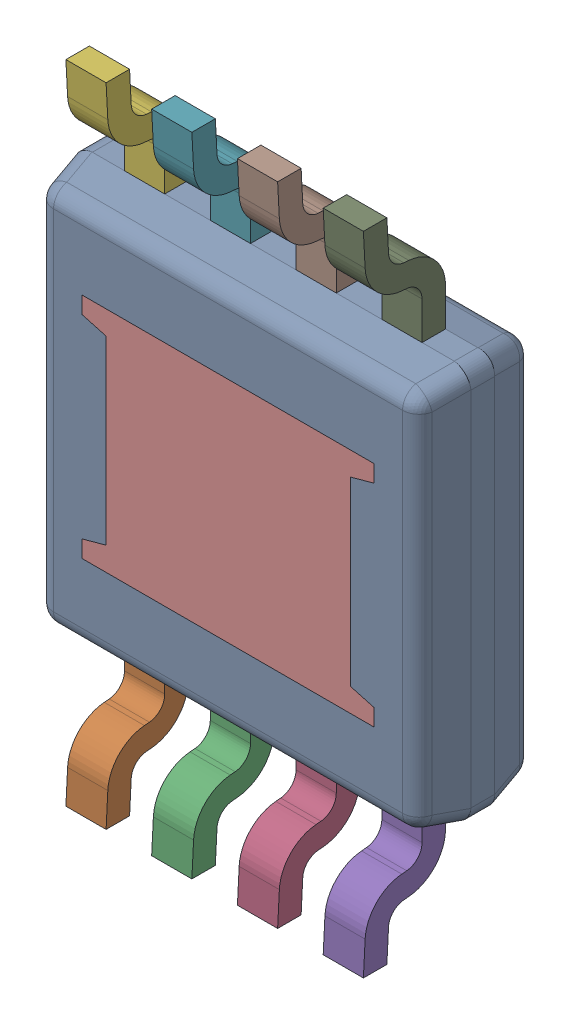
SolidWorks assembly U600_2PCB, configuration Default. Lengths in mm.
Overall size (3 4.9 0.97).
11 component instances, 3 part files, 0 mates.
Components (placement in the parent):
- MUY08A_ASM-1: MUY08A_ASM [Default] at (101.9036 103.5501 -2.2638) x (-1 0 0) z (0 -1 0) size (3 0.97 4.9)
  - BODY_MUY08A-1: BODY_MUY08A [Default] at origin size (3 0.86 3)
  - LEAD_MUY08A-1: LEAD_MUY08A [Default] at (0.9754 -0.3683 1.9177) size (0.31 0.62 0.95)
  - LEAD_MUY08A-2: LEAD_MUY08A [Default] at (0.3251 -0.3683 1.9177) size (0.31 0.62 0.95)
  - LEAD_MUY08A-3: LEAD_MUY08A [Default] at (-0.3251 -0.3683 1.9177) size (0.31 0.62 0.95)
  - LEAD_MUY08A-4: LEAD_MUY08A [Default] at (-0.9754 -0.3683 1.9177) size (0.31 0.62 0.95)
  - LEAD_MUY08A-5: LEAD_MUY08A [Default] at (0.9754 -0.3683 -1.9177) x (-1 0 0) z (0 0 -1) size (0.31 0.62 0.95)
  - LEAD_MUY08A-6: LEAD_MUY08A [Default] at (0.3251 -0.3683 -1.9177) x (-1 0 0) z (0 0 -1) size (0.31 0.62 0.95)
  - LEAD_MUY08A-7: LEAD_MUY08A [Default] at (-0.3251 -0.3683 -1.9177) x (-1 0 0) z (0 0 -1) size (0.31 0.62 0.95)
  - LEAD_MUY08A-8: LEAD_MUY08A [Default] at (-0.9754 -0.3683 -1.9177) x (-1 0 0) z (0 0 -1) size (0.31 0.62 0.95)
  - EXP_PAD_MUY08A-1: EXP_PAD_MUY08A [Default] at (0 -0.3429 0) size (2.21 0.3 1.73)
